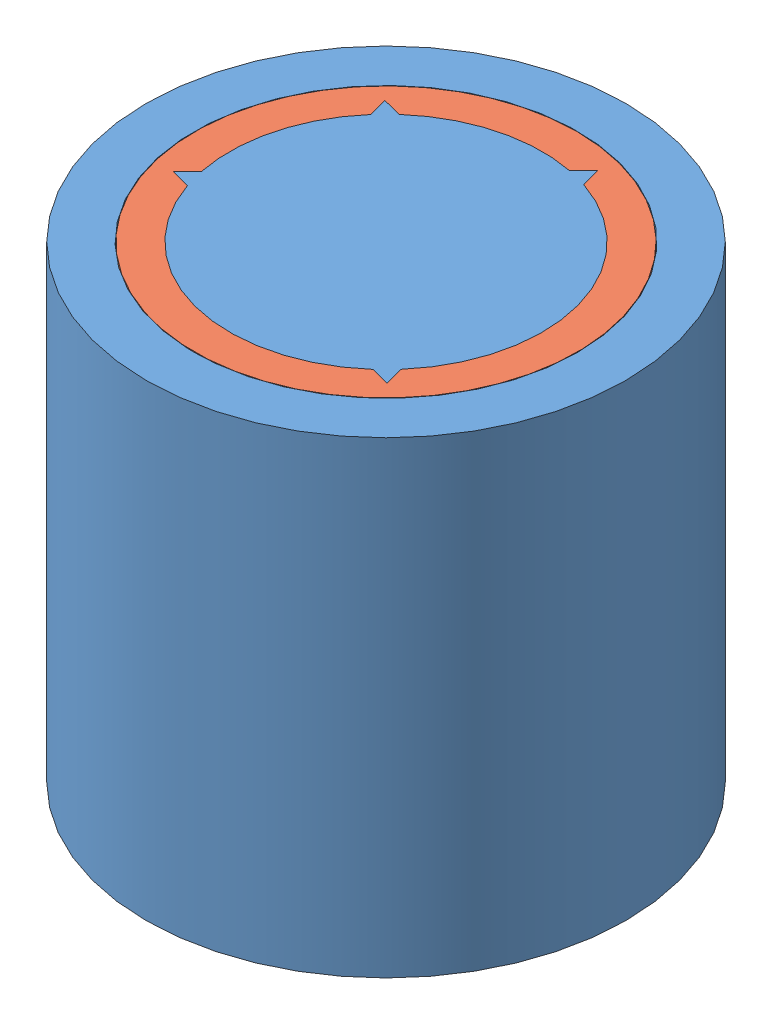
SolidWorks assembly MoldAssmably, configuration Standard. Lengths in mm.
Overall size (40 39 40).
2 component instances, 2 part files, 2 mates.
Components (placement in the parent):
- ShellV1_0_0-1: ShellV1_0_0 [Standard] at (-65.9691 -19.7207 40) size (40 39 40)
- TPERing_V1_0_3_MoldV_SAK-1: TPERing_V1_0_3_MoldV_SAK [Standard] at (-65.9691 -9.7207 40) x (0.967081 0 0.254469) z (-0.254469 0 0.967081) size (31.85 29 31.85)
Mates (geometry in assembly coordinates):
- Konzentrisch1: concentric aligned: cylinder of ShellV1_0_0-1 through (-65.9691 19.2793 40) axis (0 -1 0) radius 20; cylinder of TPERing_V1_0_3_MoldV_SAK-1 through (-65.9691 19.2793 40) axis (0 -1 0) radius 15.925
- Abstand1: distance = 10 mm aligned: plane of TPERing_V1_0_3_MoldV_SAK-1 through (-65.9691 -9.7207 40) normal (0 -1 0); plane of ShellV1_0_0-1 through (-65.9691 -19.7207 40) normal (0 -1 0)
